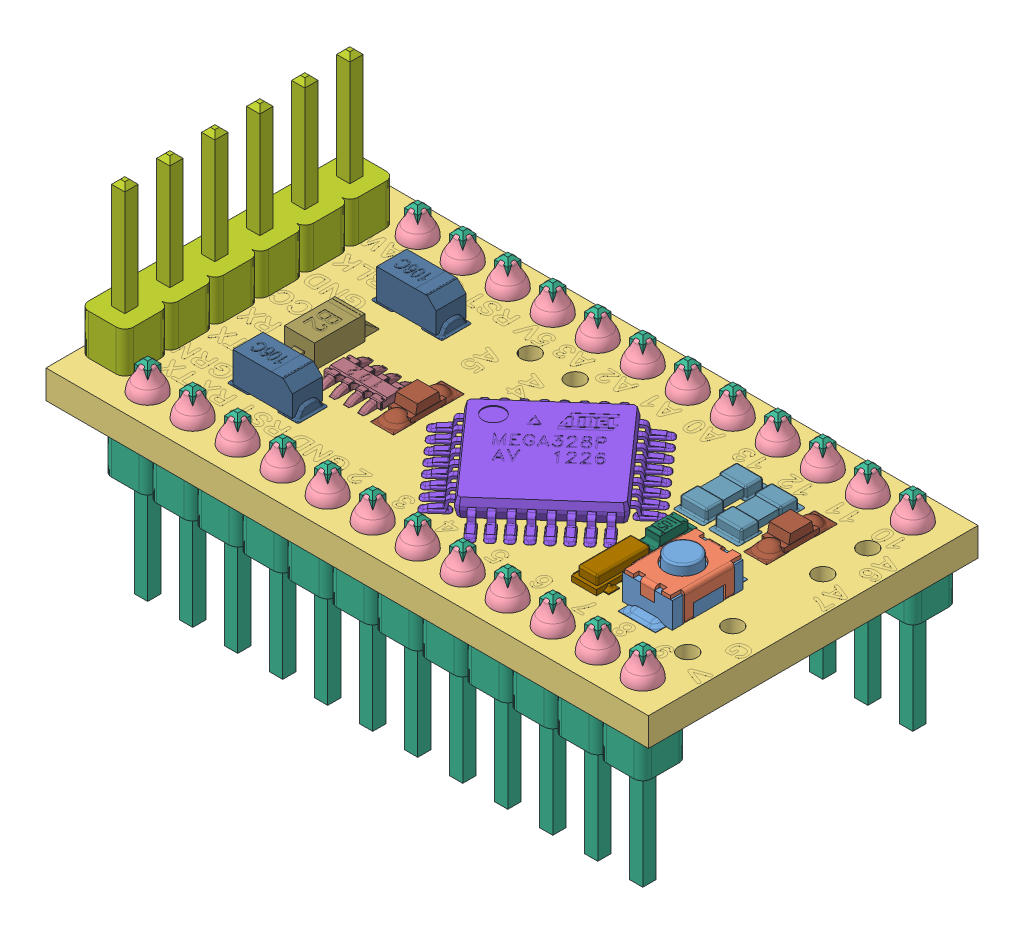
SolidWorks assembly User Library-ARDUINO_MINI_V1, configuration Default. Lengths in mm.
Overall size (34 18.6 18.6).
21 component instances, 15 part files, 0 mates.
Components (placement in the parent):
- User Library-ARDUINO_MINI_V1_ARDUINO_MINI_1-1: User Library-ARDUINO_MINI_V1_ARDUINO_MINI_1 [Default] at (18.8931 -34 -14.1188) x (0 0 1) z (0 1 0) size (18.6 34 18.6)
  - User Library-ARDUINO_MINI_V1_button_reset_1-1: User Library-ARDUINO_MINI_V1_button_reset_1 [Default] at (7.2736 10.2071 35.6) x (1 0 0) z (0 -1 0) size (5.2 2.15 3)
    - User Library-ARDUINO_MINI_V1_reset core-1: User Library-ARDUINO_MINI_V1_reset core [Default] at origin size (5.2 2.15 2.8)
    - User Library-ARDUINO_MINI_V1_reset shell-1: User Library-ARDUINO_MINI_V1_reset shell [Default] at (0 1.65 0) x (0 0 1) z (-1 0 0) size (3 1.65 4)
  - User Library-ARDUINO_MINI_V1_Mini_board_1-1: User Library-ARDUINO_MINI_V1_Mini_board_1 [Default] at (4.8188 -1.8931 34) size (18.6 34 1.6)
  - User Library-ARDUINO_MINI_V1_mini-solder-1-1: User Library-ARDUINO_MINI_V1_mini-solder-1 [Default] at (12.4388 -22.4531 33.999) x (0 1 0) z (1 0 0) size (29.74 1.5 17.04)
  - User Library-ARDUINO_MINI_V1_mini-solder-2-1: User Library-ARDUINO_MINI_V1_mini-solder-2 [Default] at (-9.1512 -2.1531 35.601) x (1 0 0) z (0 1 0) size (14.5 1.5 1.8)
  - User Library-ARDUINO_MINI_V1_12pin_header-1: User Library-ARDUINO_MINI_V1_12pin_header [Default] at (12.4388 -14.8326 34) x (1 0 0) z (0 1 0) size (2.54 11.75 30.48)
  - User Library-ARDUINO_MINI_V1_12pin_header-2: User Library-ARDUINO_MINI_V1_12pin_header [Default] at (-2.8012 -14.8326 34) x (1 0 0) z (0 1 0) size (2.54 11.75 30.48)
  - User Library-ARDUINO_MINI_V1_6pin_header-1: User Library-ARDUINO_MINI_V1_6pin_header [Default] at (11.1688 -17.3935 35.6) x (0 -1 0) z (-1 0 0) size (2.54 11.75 15.24)
  - User Library-ARDUINO_MINI_V1_atmega328-1: User Library-ARDUINO_MINI_V1_atmega328 [Default] at (5.1227 0.4003 35.7) x (0.66262 -0.748956 0) z (-0.748956 -0.66262 0) size (10 1.1 10)
  - User Library-ARDUINO_MINI_V1_16mhz crystal - measured-1: User Library-ARDUINO_MINI_V1_16mhz crystal - measured [Default] at (8.0304 7.0786 35.6) x (1 0 0) z (0 -1 0) size (3.4 0.8 2)
  - User Library-ARDUINO_MINI_V1_cap106C-1: User Library-ARDUINO_MINI_V1_cap106C [Default] at (8.8938 -11.0448 35.6) x (1 0 0) z (0 -1 0) size (1.7 1.81 4)
  - User Library-ARDUINO_MINI_V1_cap106C-2: User Library-ARDUINO_MINI_V1_cap106C [Default] at (0.7785 -11.0448 35.6) x (1 0 0) z (0 -1 0) size (1.7 1.81 4)
  - User Library-ARDUINO_MINI_V1_led-1: User Library-ARDUINO_MINI_V1_led [Default] at (5.5955 -6.4562 35.6) x (1 0 0) z (0 -1 0) size (4 0.86 1.35)
  - User Library-ARDUINO_MINI_V1_led-2: User Library-ARDUINO_MINI_V1_led [Default] at (1.4134 10.422 35.6) x (1 0 0) z (0 -1 0) size (4 0.86 1.35)
  - User Library-ARDUINO_MINI_V1_NANO DIODE-1: User Library-ARDUINO_MINI_V1_NANO DIODE [Default] at (5.2494 -12.0297 35.6) x (1 0 0) z (0 -1 0) size (4.92 1.36 1.7)
  - User Library-ARDUINO_MINI_V1_102 RESISTOR PACK-1: User Library-ARDUINO_MINI_V1_102 RESISTOR PACK [Default] at (6.0229 -8.9591 35.6) x (0 -1 0) z (-1 0 0) size (3.2 0.46 3)
  - User Library-ARDUINO_MINI_V1_smt_resistor222-1: User Library-ARDUINO_MINI_V1_smt_resistor222 [Default] at (1.4153 6.538 35.6) x (0 1 0) z (1 0 0) size (1.7 0.6 3.8)
  - User Library-ARDUINO_MINI_V1_smt_resistor222-2: User Library-ARDUINO_MINI_V1_smt_resistor222 [Default] at (1.422 8.5266 35.6) x (0 1 0) z (1 0 0) size (1.7 0.6 3.8)
  - User Library-ARDUINO_MINI_V1_603 resistor-1: User Library-ARDUINO_MINI_V1_603 resistor [Default] at (4.8327 6.8612 35.6) x (1 0 0) z (0 -1 0) size (2.36 0.61 1.03)
